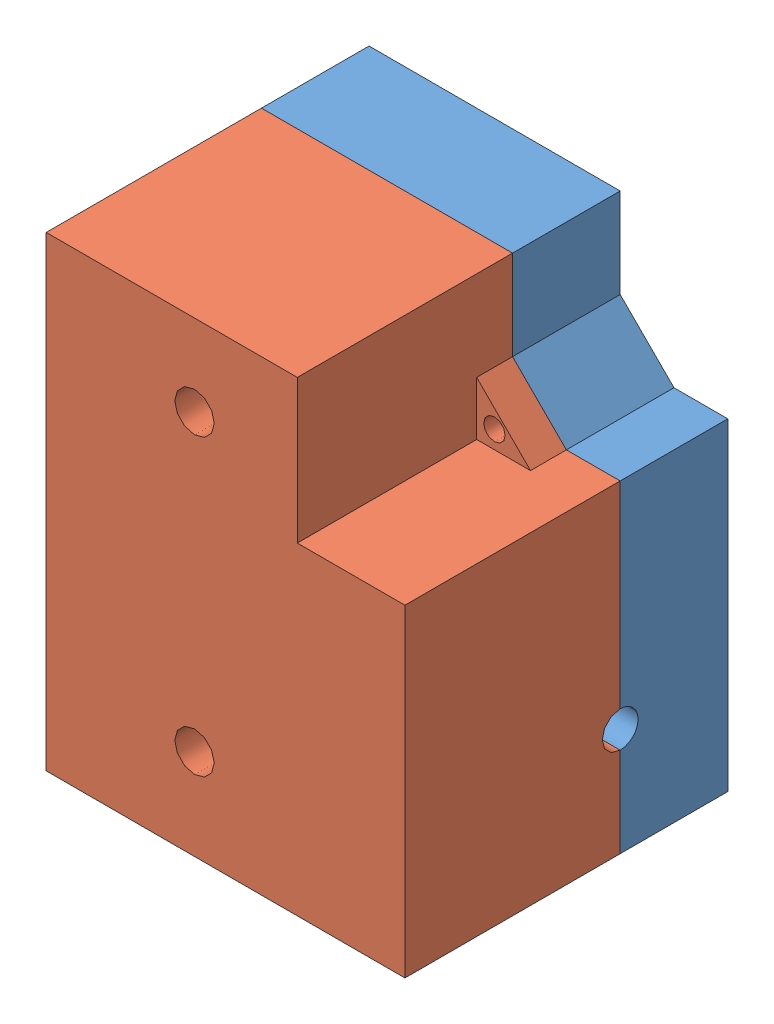
SolidWorks assembly Kutiq, configuration Default. Lengths in mm.
Overall size (56.05 71.05 45).
2 component instances, 2 part files, 3 mates.
Components (placement in the parent):
- osnova-1: osnova [Default] at (24.5101 33.2853 -7.5) size (56.05 71.05 15)
- kapak-1: kapak [Default] at (24.5101 33.2853 7.5) size (56.05 71.05 30)
Mates (geometry in assembly coordinates):
- Coincident1: coincident aligned: plane of osnova-1 through (11.8396 -57.3724 7.5) normal (1 0 0); plane of kapak-1 through (11.8396 -57.3724 12.5) normal (1 0 0)
- Coincident2: coincident aligned: plane of osnova-1 through (-38.1604 -57.3724 7.5) normal (0 -1 0); plane of kapak-1 through (11.8396 -57.3724 12.5) normal (0 -1 0)
- Coincident3: coincident anti-aligned: plane of osnova-1 through (-38.1604 -57.3724 7.5) normal (0 0 1); plane of kapak-1 through (-38.1604 -57.3724 7.5) normal (0 0 -1)
